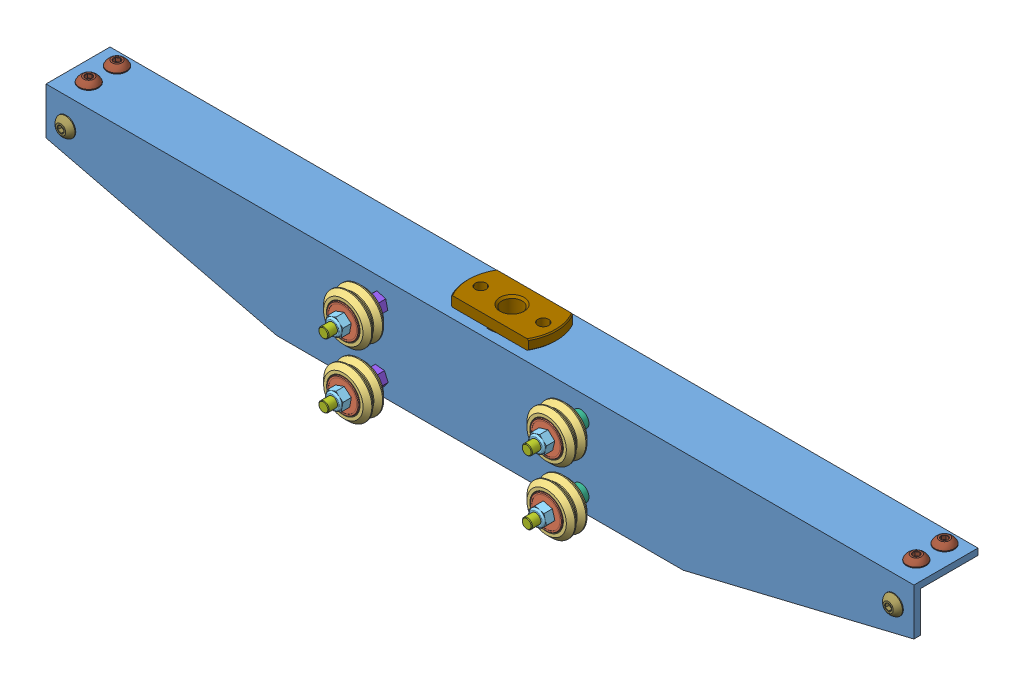
SolidWorks assembly Z_Gantry_Angle_Plate, configuration Default. Lengths in mm.
Overall size (430 65.17 58.58).
44 component instances, 12 part files, 39 mates.
Components (placement in the parent):
- Z_Gantry_Plate-1: Z_Gantry_Plate [Default] at origin size (430 50.8 31.75)
- Dual_V_Wheel_Bolt_Assembly-1: Dual_V_Wheel_Bolt_Assembly [Default] at (50 -42.8 -4.675) x (-0.831081 0.556151 0) z (0.556151 0.831081 0) size (24.11 31.5 24.11) (flexible)
  - Ball_Bearing_625_2RS-1: Ball_Bearing_625_2RS [Défaut] at (0 13.525 0) x (-1 0 0) z (0 0 1) size (16 5 16)
  - Ball_Bearing_625_2RS-2: Ball_Bearing_625_2RS [Défaut] at (0 19.525 0) x (-0.965595 0 -0.260051) z (-0.260051 0 0.965595) size (16 5 16)
  - Dual_V_Wheel_Delrin_(5mm_Bore)-1: Dual_V_Wheel_Delrin_(5mm_Bore) [Défaut] at (0 11.41 0) x (0.999956 0 0.009415) z (-0.009415 0 0.999956) size (23.89 10.23 23.89)
  - Precision_Shim_10x5x1mm-1: Precision_Shim_10x5x1mm [Default] at (0 16.525 0) x (-0.674323 0 -0.738436) z (-0.738436 0 0.674323) size (10 1 10)
  - Nylon_Insert_Hex_Locknut_5mm-1: Nylon_Insert_Hex_Locknut_5mm [Default] at (0 22.025 0) x (0.336542 0 0.941668) z (-0.941668 0 0.336542) size (8 4.99 9.24)
  - Aluminium_Spacer-1: Aluminium_Spacer [Défaut] at (0 7.85 0) x (-0.619579 0 0.784934) z (0 -1 0) size (8 8 6.35)
  - M5_Low_Profile_Screw_30mm-1: M5_Low_Profile_Screw_30mm [Default] at origin size (9 31.5 9)
- Dual_V_Wheel_Bolt_Assembly-2: Dual_V_Wheel_Bolt_Assembly [Default] at (50 -11.175 -4.675) x (0.333901 -0.942608 0) z (-0.942608 -0.333901 0) size (29.34 31.5 29.34) (flexible)
  - Ball_Bearing_625_2RS-1: Ball_Bearing_625_2RS [Défaut] at (0 13.525 0) x (-1 0 0) z (0 0 1) size (16 5 16)
  - Ball_Bearing_625_2RS-2: Ball_Bearing_625_2RS [Défaut] at (0 19.525 0) x (-0.965595 0 -0.260051) z (-0.260051 0 0.965595) size (16 5 16)
  - Dual_V_Wheel_Delrin_(5mm_Bore)-1: Dual_V_Wheel_Delrin_(5mm_Bore) [Défaut] at (0 11.41 0) x (0.964694 0 -0.263375) z (0.263375 0 0.964694) size (23.89 10.23 23.89)
  - Precision_Shim_10x5x1mm-1: Precision_Shim_10x5x1mm [Default] at (0 16.525 0) x (-0.674323 0 -0.738436) z (-0.738436 0 0.674323) size (10 1 10)
  - Nylon_Insert_Hex_Locknut_5mm-1: Nylon_Insert_Hex_Locknut_5mm [Default] at (0 22.025 0) x (0.457359 0 0.889282) z (-0.889282 0 0.457359) size (8 4.99 9.24)
  - Aluminium_Spacer-1: Aluminium_Spacer [Défaut] at (0 7.85 0) x (0.780963 0 0.624577) z (0 -1 0) size (8 8 6.35)
  - M5_Low_Profile_Screw_30mm-1: M5_Low_Profile_Screw_30mm [Default] at origin size (9 31.5 9)
- Dual_V_Wheel_Bolt_Assembly_Eccentric-1: Dual_V_Wheel_Bolt_Assembly_Eccentric [Default] at (-50.7692 -11.3552 -4.675) x (1 0 0) z (0 -1 0) size (27.28 31.5 27.28) (flexible)
  - Ball_Bearing_625_2RS-1: Ball_Bearing_625_2RS [Défaut] at (0 13.525 0) x (-1 0 0) z (0 0 1) size (16 5 16)
  - Ball_Bearing_625_2RS-2: Ball_Bearing_625_2RS [Défaut] at (0 19.525 0) x (-0.965595 0 -0.260051) z (-0.260051 0 0.965595) size (16 5 16)
  - Dual_V_Wheel_Delrin_(5mm_Bore)-1: Dual_V_Wheel_Delrin_(5mm_Bore) [Défaut] at (0 11.41 0) x (0.988093 0 -0.153859) z (0.153859 0 0.988093) size (23.89 10.23 23.89)
  - Precision_Shim_10x5x1mm-1: Precision_Shim_10x5x1mm [Default] at (0 16.525 0) x (-0.674323 0 -0.738436) z (-0.738436 0 0.674323) size (10 1 10)
  - Nylon_Insert_Hex_Locknut_5mm-1: Nylon_Insert_Hex_Locknut_5mm [Default] at (0 22.025 0) x (0.336542 0 0.941668) z (-0.941668 0 0.336542) size (8 4.99 9.24)
  - M5_Low_Profile_Screw_30mm-1: M5_Low_Profile_Screw_30mm [Default] at origin size (9 31.5 9)
  - Eccentric_Spacer-1: Eccentric_Spacer [Défaut] at (0.7692 4.675 -0.1802) x (-0.228054 0 -0.973648) z (0 1 0) size (9.99 7.87 7.62)
- Dual_V_Wheel_Bolt_Assembly_Eccentric-2: Dual_V_Wheel_Bolt_Assembly_Eccentric [Default] at (-50.7252 -43.1133 -4.675) x (1 0 0) z (0 -1 0) size (33.21 31.5 33.21) (flexible)
  - Ball_Bearing_625_2RS-1: Ball_Bearing_625_2RS [Défaut] at (0 13.525 0) x (-1 0 0) z (0 0 1) size (16 5 16)
  - Ball_Bearing_625_2RS-2: Ball_Bearing_625_2RS [Défaut] at (0 19.525 0) x (-0.965595 0 -0.260051) z (-0.260051 0 0.965595) size (16 5 16)
  - Dual_V_Wheel_Delrin_(5mm_Bore)-1: Dual_V_Wheel_Delrin_(5mm_Bore) [Défaut] at (0 11.41 0) x (0.565015 0 -0.825081) z (0.825081 0 0.565015) size (23.89 10.23 23.89)
  - Precision_Shim_10x5x1mm-1: Precision_Shim_10x5x1mm [Default] at (0 16.525 0) x (-0.674323 0 -0.738436) z (-0.738436 0 0.674323) size (10 1 10)
  - Nylon_Insert_Hex_Locknut_5mm-1: Nylon_Insert_Hex_Locknut_5mm [Default] at (0 22.025 0) x (0.336542 0 0.941668) z (-0.941668 0 0.336542) size (8 4.99 9.24)
  - M5_Low_Profile_Screw_30mm-1: M5_Low_Profile_Screw_30mm [Default] at origin size (9 31.5 9)
  - Eccentric_Spacer-1: Eccentric_Spacer [Défaut] at (0.7252 4.675 -0.3133) x (-0.396609 0 -0.917988) z (0 1 0) size (9.99 7.87 7.62)
- MTSRN12-1: MTSRN12 [Default] at (0 5 -15.875) x (0 -1 0) z (0 0 1) size (30 44 23)
- HNTTSN5-5-1: HNTTSN5-5 [Default] at (-205 -4.375 -11.176) x (0 1 0) z (0 0 1) size (4.3 10 10)
- HNTTSN5-5-3: HNTTSN5-5 [Default] at (-205 -4.375 -25.176) x (0 1 0) z (0 0 1) size (4.3 10 10)
- HNTTSN5-5-4: HNTTSN5-5 [Default] at (205 -4.375 -11.176) x (0 1 0) z (0 0 1) size (4.3 10 10)
- HNTTSN5-5-6: HNTTSN5-5 [Default] at (205 -4.375 -25.176) x (0 1 0) z (0 0 1) size (4.3 10 10)
- 5mmX8mm_Buttonhead(McMaster_94500A230)-7: 5mmX8mm_Buttonhead(McMaster_94500A230) [94500A230] at (205 2.75 -25.176) x (0.075751 0 -0.997127) z (0 1 0) size (9.5 9.5 11.19)
- 5mmX8mm_Buttonhead(McMaster_94500A230)-8: 5mmX8mm_Buttonhead(McMaster_94500A230) [94500A230] at (205 2.75 -11.176) x (1 0 0) z (0 1 0) size (9.5 9.5 11.19)
- 5mmX10mm_Buttonhead(McMaster_91239A224)-3: 5mmX10mm_Buttonhead(McMaster_91239A224) [91239A224] at (205 -13.175 2.75) size (9.5 9.5 13.21)
- 5mmX10mm_Buttonhead(McMaster_91239A224)-4: 5mmX10mm_Buttonhead(McMaster_91239A224) [91239A224] at (-205 -13.175 2.75) size (9.5 9.5 13.21)
- 5mmX8mm_Buttonhead(McMaster_94500A230)-5: 5mmX8mm_Buttonhead(McMaster_94500A230) [94500A230] at (-205 2.75 -25.176) x (1 0 0) z (0 1 0) size (9.5 9.5 11.19)
- 5mmX8mm_Buttonhead(McMaster_94500A230)-6: 5mmX8mm_Buttonhead(McMaster_94500A230) [94500A230] at (-205 2.75 -11.176) x (1 0 0) z (0 1 0) size (9.5 9.5 11.19)
Mates (geometry in assembly coordinates):
- Concentric1: concentric aligned: cylinder of Z_Gantry_Plate-1 through (50 -11.175 0) axis (0 0 -1) radius 2.5; cylinder of Dual_V_Wheel_Bolt_Assembly-2/M5_Low_Profile_Screw_30mm-1 through (50 -11.175 26.825) axis (0 0 -1) radius 2.5
- Coincident5: coincident anti-aligned: plane of Z_Gantry_Plate-1 through (215 -50.8 0) normal (0 0 1); plane of Dual_V_Wheel_Bolt_Assembly-2/Aluminium_Spacer-1 through (50 -11.175 0) normal (0 0 -1)
- Coincident6: coincident anti-aligned: plane of Z_Gantry_Plate-1 through (215 -3.175 -3.175) normal (0 0 -1); plane of Dual_V_Wheel_Bolt_Assembly-2/M5_Low_Profile_Screw_30mm-1 through (50 -11.175 -3.175) normal (0 0 1)
- Concentric2: concentric aligned: cylinder of Z_Gantry_Plate-1 through (50 -42.8 0) axis (0 0 -1) radius 2.5; cylinder of Dual_V_Wheel_Bolt_Assembly-1/M5_Low_Profile_Screw_30mm-1 through (50 -42.8 26.825) axis (0 0 -1) radius 2.5
- Coincident7: coincident anti-aligned: plane of Z_Gantry_Plate-1 through (215 -50.8 0) normal (0 0 1); plane of Dual_V_Wheel_Bolt_Assembly-1/Aluminium_Spacer-1 through (50 -42.8 0) normal (0 0 -1)
- Coincident9: coincident anti-aligned: plane of Z_Gantry_Plate-1 through (215 -3.175 -3.175) normal (0 0 -1); plane of Dual_V_Wheel_Bolt_Assembly-1/M5_Low_Profile_Screw_30mm-1 through (50 -42.8 -3.175) normal (0 0 1)
- Concentric3: concentric anti-aligned: cylinder of Z_Gantry_Plate-1 through (-50 -11.175 0) axis (0 0 -1) radius 3.57; cylinder of Dual_V_Wheel_Bolt_Assembly_Eccentric-1/Eccentric_Spacer-1 through (-50 -11.175 -1.27) axis (0 0 1) radius 3.555
- Coincident10: coincident anti-aligned: plane of Z_Gantry_Plate-1 through (215 -50.8 0) normal (0 0 1); plane of Dual_V_Wheel_Bolt_Assembly_Eccentric-1/Eccentric_Spacer-1 through (-51.0362 -6.751 0) normal (0 0 -1)
- Coincident11: coincident anti-aligned: plane of Z_Gantry_Plate-1 through (215 -3.175 -3.175) normal (0 0 -1); plane of Dual_V_Wheel_Bolt_Assembly_Eccentric-1/M5_Low_Profile_Screw_30mm-1 through (-50.7692 -11.3552 -3.175) normal (0 0 1)
- Concentric5: concentric anti-aligned: cylinder of Z_Gantry_Plate-1 through (-50 -42.8 0) axis (0 0 -1) radius 3.57; cylinder of Dual_V_Wheel_Bolt_Assembly_Eccentric-2/Eccentric_Spacer-1 through (-50 -42.8 -1.27) axis (0 0 1) radius 3.555
- Coincident12: coincident anti-aligned: plane of Z_Gantry_Plate-1 through (215 -50.8 0) normal (0 0 1); plane of Dual_V_Wheel_Bolt_Assembly_Eccentric-2/Eccentric_Spacer-1 through (-51.8021 -38.6289 0) normal (0 0 -1)
- Coincident13: coincident anti-aligned: plane of Z_Gantry_Plate-1 through (215 -3.175 -3.175) normal (0 0 -1); plane of Dual_V_Wheel_Bolt_Assembly_Eccentric-2/M5_Low_Profile_Screw_30mm-1 through (-50.7252 -43.1133 -3.175) normal (0 0 1)
- Concentric6: concentric anti-aligned: cylinder of Z_Gantry_Plate-1 through (0 0.001 -15.875) axis (0 -1 0) radius 11.1125; cylinder of MTSRN12-1 through (0 -25 -15.875) axis (0 1 0) radius 11
- Parallel1: parallel anti-aligned: plane of Z_Gantry_Plate-1 through (215 -3.175 -3.175) normal (0 0 -1); plane of MTSRN12-1 through (19.0526 -39.6611 -4.875) normal (0 0 1)
- Coincident15: coincident anti-aligned: plane of Z_Gantry_Plate-1 through (215 0 0) normal (0 1 0); plane of MTSRN12-1 through (21.5 0 -15.875) normal (0 -1 0)
- Concentric7: concentric anti-aligned: cylinder of Z_Gantry_Plate-1 through (-205 -3.175 -11.176) axis (0 1 0) radius 2.5; cylinder of HNTTSN5-5-1 through (-205 -4.375 -11.176) axis (0 -1 0) radius 2.067
- Concentric8: concentric anti-aligned: cylinder of Z_Gantry_Plate-1 through (-205 -3.175 -25.176) axis (0 1 0) radius 2.5; cylinder of HNTTSN5-5-3 through (-205 -4.375 -25.176) axis (0 -1 0) radius 2.067
- Concentric9: concentric anti-aligned: cylinder of Z_Gantry_Plate-1 through (205 -3.175 -11.176) axis (0 1 0) radius 2.5; cylinder of HNTTSN5-5-4 through (205 -4.375 -11.176) axis (0 -1 0) radius 2.067
- Concentric10: concentric anti-aligned: cylinder of Z_Gantry_Plate-1 through (205 -3.175 -25.176) axis (0 1 0) radius 2.5; cylinder of HNTTSN5-5-6 through (205 -4.375 -25.176) axis (0 -1 0) radius 2.067
- Parallel2: parallel aligned: plane of Z_Gantry_Plate-1 through (215 0 -31.75) normal (0 0 -1); plane of HNTTSN5-5-1 through (-205 -4.375 -16.176) normal (0 0 -1)
- Parallel3: parallel aligned: plane of Z_Gantry_Plate-1 through (215 0 -31.75) normal (0 0 -1); plane of HNTTSN5-5-3 through (-205 -4.375 -30.176) normal (0 0 -1)
- Parallel4: parallel aligned: plane of Z_Gantry_Plate-1 through (215 0 -31.75) normal (0 0 -1); plane of HNTTSN5-5-4 through (205 -4.375 -16.176) normal (0 0 -1)
- Parallel5: parallel aligned: plane of Z_Gantry_Plate-1 through (215 0 -31.75) normal (0 0 -1); plane of HNTTSN5-5-6 through (205 -4.375 -30.176) normal (0 0 -1)
- Distance1: distance = 2 mm anti-aligned: plane of Z_Gantry_Plate-1 through (215 -3.175 -31.75) normal (0 -1 0); plane of HNTTSN5-5-4 through (202.1 -5.175 -6.176) normal (0 1 0)
- Distance2: distance = 2 mm anti-aligned: plane of Z_Gantry_Plate-1 through (215 -3.175 -31.75) normal (0 -1 0); plane of HNTTSN5-5-6 through (202.1 -5.175 -20.176) normal (0 1 0)
- Distance3: distance = 2 mm anti-aligned: plane of Z_Gantry_Plate-1 through (215 -3.175 -31.75) normal (0 -1 0); plane of HNTTSN5-5-3 through (-207.9 -5.175 -20.176) normal (0 1 0)
- Distance4: distance = 2 mm anti-aligned: plane of Z_Gantry_Plate-1 through (215 -3.175 -31.75) normal (0 -1 0); plane of HNTTSN5-5-1 through (-207.9 -5.175 -6.176) normal (0 1 0)
- Concentric11: concentric aligned: cylinder of Z_Gantry_Plate-1 through (-205 -3.175 -25.176) axis (0 1 0) radius 2.5; cylinder of 5mmX8mm_Buttonhead(McMaster_94500A230)-5 through (-205 2.75 -25.176) axis (0 1 0) radius 4.75
- Concentric12: concentric aligned: cylinder of Z_Gantry_Plate-1 through (-205 -3.175 -11.176) axis (0 1 0) radius 2.5; cylinder of 5mmX8mm_Buttonhead(McMaster_94500A230)-6 through (-205 2.75 -11.176) axis (0 1 0) radius 4.75
- Coincident23: coincident anti-aligned: plane of Z_Gantry_Plate-1 through (215 0 0) normal (0 1 0); plane of 5mmX8mm_Buttonhead(McMaster_94500A230)-6 through (-205 0 -6.426) normal (0 -1 0)
- Coincident24: coincident anti-aligned: plane of Z_Gantry_Plate-1 through (215 0 0) normal (0 1 0); plane of 5mmX8mm_Buttonhead(McMaster_94500A230)-5 through (-205 0 -20.426) normal (0 -1 0)
- Concentric13: concentric aligned: cylinder of Z_Gantry_Plate-1 through (-205 -13.175 -10.5289) axis (0 0 1) radius 2.6; cylinder of 5mmX10mm_Buttonhead(McMaster_91239A224)-4 through (-205 -13.175 2.75) axis (0 0 1) radius 4.75
- Coincident25: coincident anti-aligned: plane of Z_Gantry_Plate-1 through (215 -50.8 0) normal (0 0 1); plane of 5mmX10mm_Buttonhead(McMaster_91239A224)-4 through (-205 -17.925 0) normal (0 0 -1)
- Concentric14: concentric aligned: cylinder of Z_Gantry_Plate-1 through (205 -3.175 -25.176) axis (0 1 0) radius 2.5; cylinder of 5mmX8mm_Buttonhead(McMaster_94500A230)-7 through (205 2.75 -25.176) axis (0 1 0) radius 4.75
- Coincident26: coincident anti-aligned: plane of Z_Gantry_Plate-1 through (215 0 0) normal (0 1 0); plane of 5mmX8mm_Buttonhead(McMaster_94500A230)-7 through (209.7364 0 -24.8162) normal (0 -1 0)
- Concentric15: concentric aligned: cylinder of Z_Gantry_Plate-1 through (205 -3.175 -11.176) axis (0 1 0) radius 2.5; cylinder of 5mmX8mm_Buttonhead(McMaster_94500A230)-8 through (205 2.75 -11.176) axis (0 1 0) radius 4.75
- Coincident27: coincident anti-aligned: plane of Z_Gantry_Plate-1 through (215 0 0) normal (0 1 0); plane of 5mmX8mm_Buttonhead(McMaster_94500A230)-8 through (205 0 -6.426) normal (0 -1 0)
- Concentric16: concentric aligned: cylinder of Z_Gantry_Plate-1 through (205 -13.175 -10.5289) axis (0 0 1) radius 2.6; cylinder of 5mmX10mm_Buttonhead(McMaster_91239A224)-3 through (205 -13.175 2.75) axis (0 0 1) radius 4.75
- Coincident28: coincident anti-aligned: plane of Z_Gantry_Plate-1 through (215 -50.8 0) normal (0 0 1); plane of 5mmX10mm_Buttonhead(McMaster_91239A224)-3 through (205 -17.925 0) normal (0 0 -1)
